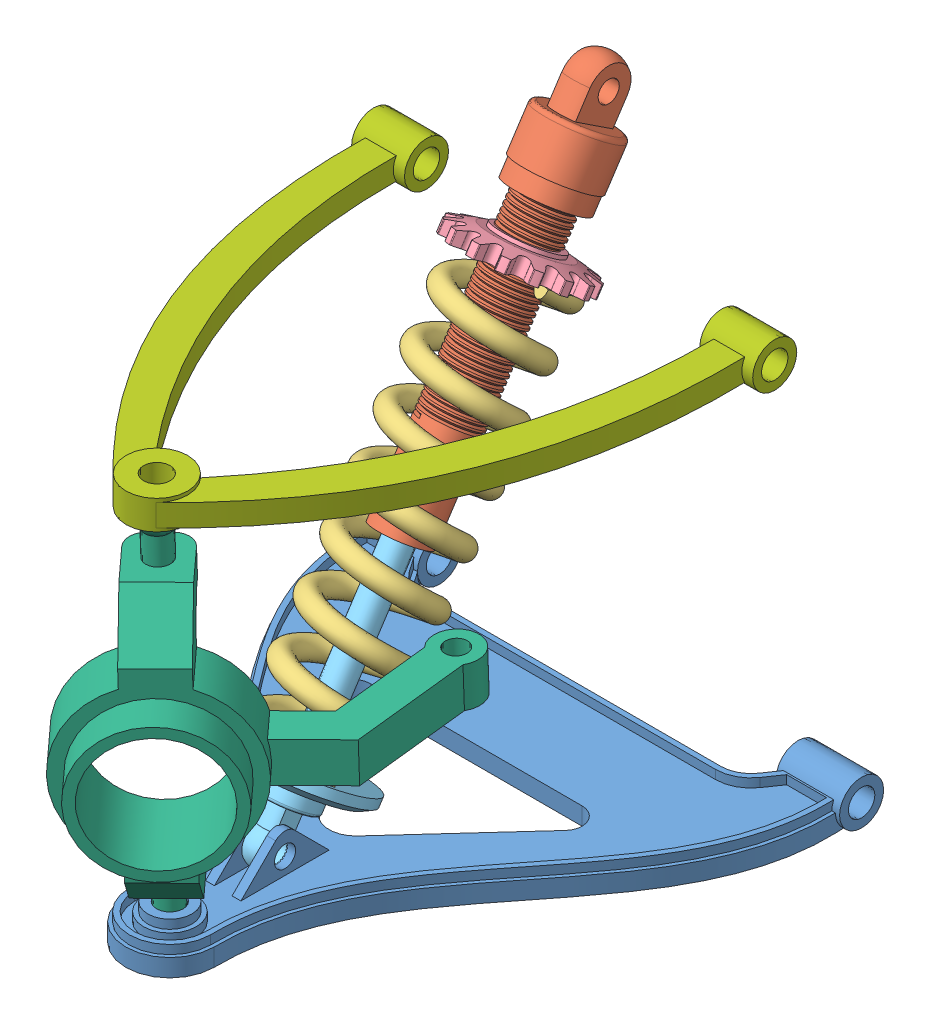
SolidWorks assembly SuspensionV1, configuration Default. Lengths in mm.
Overall size (276.95 357.43 369.82).
8 component instances, 7 part files, 4 mates.
Components (placement in the parent):
- HolderInferior-1: HolderInferior [Predeterminado] at origin size (276.95 34.39 291.93)
- Shock Absorber-1: Shock Absorber [Default] at (0 218.7905 -74.8267) x (0 0.549915 0.835221) z (-1 0 0) size (98.64 363 98.64)
  - BaseRosca-2: BaseRosca [Predeterminado] at origin size (43 215 43)
  - Spring-2: Spring [Predeterminado] at (0 -97.5 0) x (0.408238 0 -0.912876) z (0.912876 0 0.408238) size (63.95 244 65.19)
  - Tuerca-1: Tuerca [Predeterminado] at (0 12.5 0) x (0.700607 0 -0.713548) z (0.713548 0 0.700607) size (69.91 13.31 69.59)
  - Inferior-1: Inferior [Predeterminado] at (0 -175.5 0) x (0 0 -1) z (-1 0 0) size (70 160 70)
- Mangueta-1: Mangueta [Predeterminado] at (26.5079 106.1452 147.9849) x (-0.738776 -0.026391 0.673434) z (-0.673614 -0.002664 -0.739078) size (174 219.14 107.7)
- SupWishbone-1: SupWishbone [Predeterminado] at (-4.2414 210.0226 118.1481) size (227.35 25 266.5)
Mates (geometry in assembly coordinates):
- Concéntrica1: concentric anti-aligned: cylinder of HolderInferior-1 through (10 14.3934 59.7496) axis (-1 0 0) radius 6; cylinder of Shock Absorber-1/Inferior-1 through (-34.5 14.3934 59.7496) axis (1 0 0) radius 6
- Ancho1: width anti-aligned: plane of HolderInferior-1 through (-5 19.3934 59.7496) normal (1 0 0); plane of Shock Absorber-1/Inferior-1 through (5 19.3934 59.7496) normal (-1 0 0); plane of HolderInferior-1 through (-5.5 94.2058 55.0921) normal (-1 0 0); plane of Shock Absorber-1/Inferior-1 through (5.5 94.2058 55.0921) normal (1 0 0)
- Concéntrica3: concentric: sphere of Mangueta-1; cylinder of SupWishbone-1 through (-4.2414 222.5226 118.1481) axis (0 -1 0) radius 7.5
- Concéntrica5: concentric: cylinder of HolderInferior-1 through (0 -5 115) axis (0 1 0) radius 7.5; sphere of Mangueta-1
